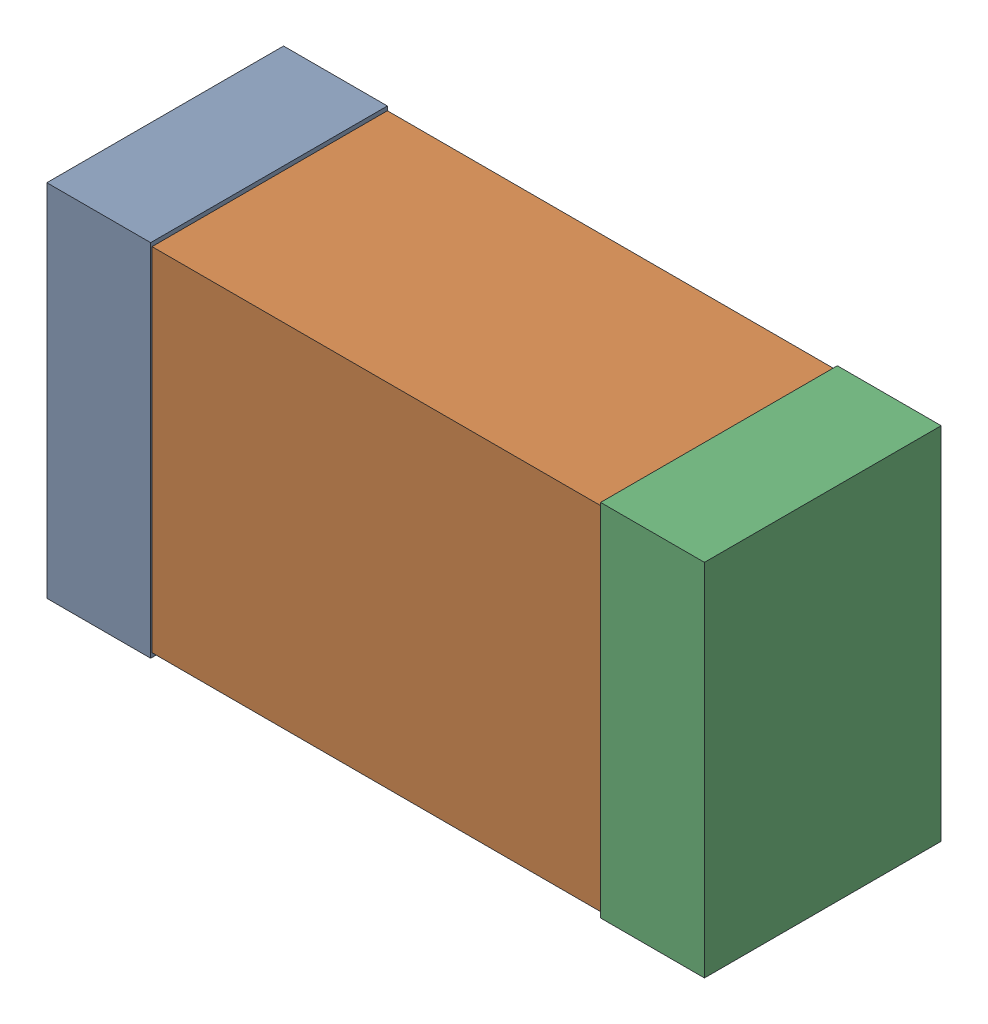
SolidWorks assembly USB67_C6, configuration Default. Lengths in mm.
Overall size (2.38 1.3 0.85).
6 component instances, 2 part files, 0 mates.
Components (placement in the parent):
- 384311232-1: 384311232 [Default] at (137.371 82.169 0) size (0.38 1.3 0.85)
  - Extruded_8-1: Extruded_8 [Default] at origin size (0.38 1.3 0.85)
- 402662800-1: 402662800 [Default] at (138.371 82.169 0) size (2.2 1.27 0.85)
  - Extruded_30-1: Extruded_30 [Default] at origin size (2.2 1.27 0.85)
- 384311232-2: 384311232 [Default] at (139.371 82.169 0) size (0.38 1.3 0.85)
  - Extruded_8-1: Extruded_8 [Default] at origin size (0.38 1.3 0.85)
